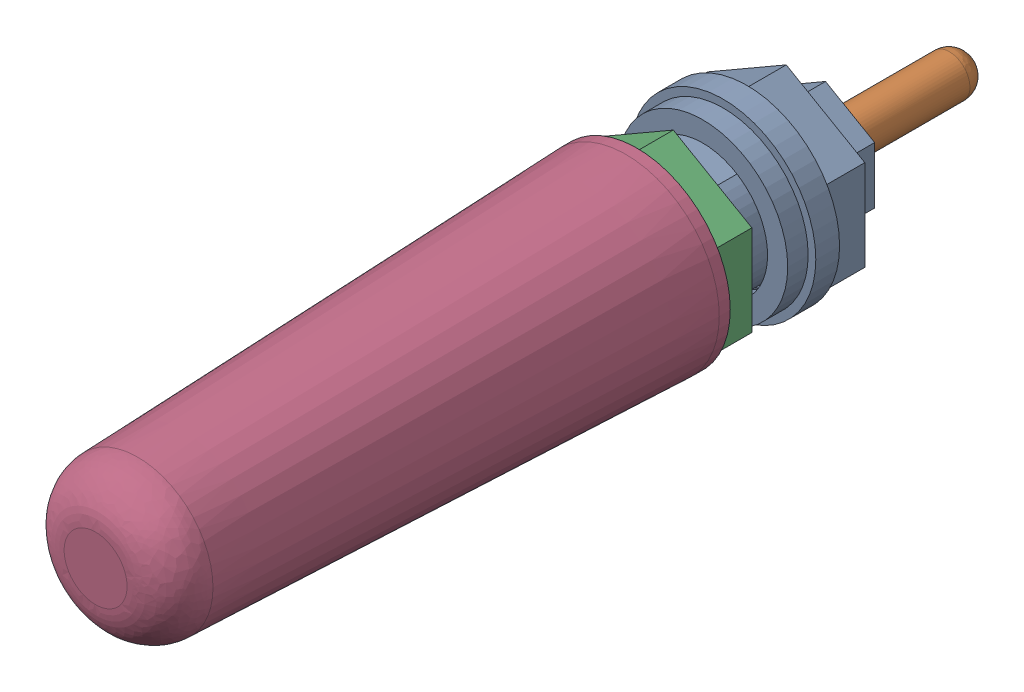
SolidWorks assembly WIFI-AT, configuration Default. Lengths in mm.
Overall size (9.5 9.5 44.46).
4 component instances, 4 part files, 0 mates.
Components (placement in the parent):
- BASE-1: BASE [Default] at origin size (9.43 9.43 15)
- WIRE-1: WIRE [Default] at origin size (2.1 2.1 7.3)
- NUT-1: NUT [Default] at (0 0 3.75) size (8 9.24 1.85)
- AT-1: AT [Default] at origin size (9.5 9.5 27.56)
